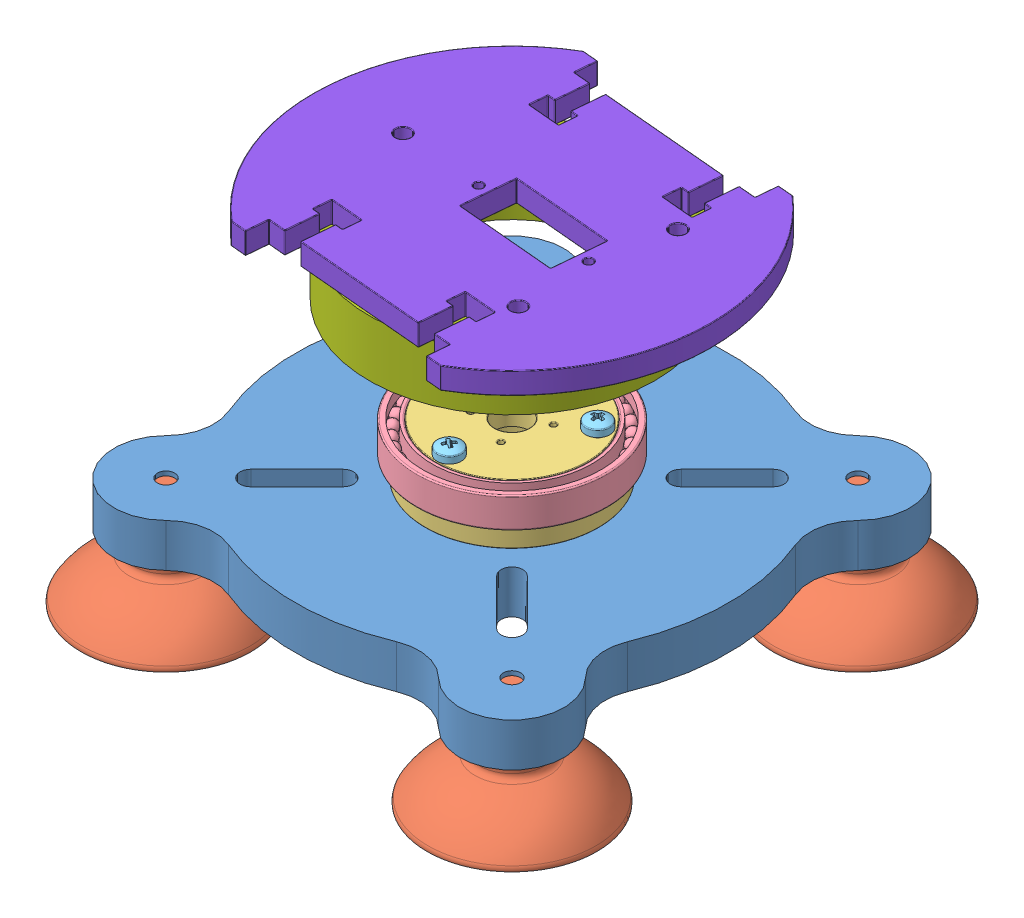
SolidWorks assembly Assem1, configuration Default. Lengths in mm.
Overall size (119.13 78.96 119.13).
15 component instances, 8 part files, 22 mates.
Components (placement in the parent):
- part_12 t310-1: part_12 t310 [Default] at origin size (103.9 10 103.9)
- part_13 t310-1: part_13 t310 [Default] at (-39.9515 -5 -39.9515) x (0 1 0) z (0 0 1) size (24.01 39.22 39.22)
- part_13 t310-5: part_13 t310 [Default] at (39.9515 -5 -39.9515) x (0 1 0) z (-1 0 0) size (24.01 39.22 39.22)
- part_13 t310-6: part_13 t310 [Default] at (39.9515 -5 39.9515) x (0 1 0) z (0 0 -1) size (24.01 39.22 39.22)
- part_13 t310-7: part_13 t310 [Default] at (-39.9515 -5 39.9515) x (0 1 0) z (1 0 0) size (24.01 39.22 39.22)
- part_11 t310-4: part_11 t310 [Default] at (0 10 0) x (0.866025 0 -0.5) z (0.5 0 0.866025) size (40 12 40)
- angular contact ball bearing_68_iso-4: angular contact ball bearing_68_iso [ISO 15 ABB - 3735 - 38,DE,NC,38_68] at (0 18.5 0) x (0 1 0) z (0.746032 0 -0.66591) size (7 44 44)
- pan head cross recess screw_iso-5: pan head cross recess screw_iso [ISO 7045 - M3 x 25 - Z - 25S] at (12.5574 25.1 -7.25) x (0 -1 0) z (0 0 1) size (27.35 5.6 5.6)
- pan head cross recess screw_iso-10: pan head cross recess screw_iso [ISO 7045 - M3 x 25 - Z - 25S] at (-12.5574 24.4 -7.25) x (0 -1 0) z (0.546944 0 -0.837169) size (27.35 5.6 5.6)
- pan head cross recess screw_iso-11: pan head cross recess screw_iso [ISO 7045 - M3 x 25 - Z - 25S] at (0 24.4 14.5) x (0 -1 0) z (0.546944 0 -0.837169) size (27.35 5.6 5.6)
- hex nut style 1 gradeab_iso-1: hex nut style 1 gradeab_iso [ISO - 4032 - M3 - D - S] at (-12.5574 2.6 -7.25) x (1 0 0) z (0 -1 0) size (5.5 6.35 2.4)
- hex nut style 1 gradeab_iso-2: hex nut style 1 gradeab_iso [ISO - 4032 - M3 - D - S] at (0 2.6 14.5) x (1 0 0) z (0 -1 0) size (5.5 6.35 2.4)
- hex nut style 1 gradeab_iso-3: hex nut style 1 gradeab_iso [ISO - 4032 - M3 - D - S] at (12.5574 2.6 -7.25) x (1 0 0) z (0 -1 0) size (5.5 6.35 2.4)
- part_10 t310-1: part_10 t310 [Default] at (0 45.9574 0) x (-0.996058 0 -0.088703) z (0.088703 0 -0.996058) size (66 13 66)
- part_9 t310-1: part_9 t310 [Default] at (0 58.9574 0) x (-0.996058 0 -0.088703) z (0.088703 0 -0.996058) size (92 5 75)
Mates (geometry in assembly coordinates):
- Concentric1: concentric anti-aligned: cylinder of part_12 t310-1 through (-39.9515 10 -39.9515) axis (0 -1 0) radius 2; cylinder of part_13 t310-1 through (-39.9515 9.0072 -39.9515) axis (0 1 0) radius 2.4
- Coincident1: coincident anti-aligned: plane of part_12 t310-1 through (0 0 0) normal (0 -1 0); plane of part_13 t310-1 through (-39.9515 0 -39.9515) normal (0 1 0)
- Concentric2: concentric aligned: cylinder of part_12 t310-1 through (12.5574 10 -7.25) axis (0 -1 0) radius 1.75; cylinder of part_11 t310-4 through (12.5574 22 -7.25) axis (0 -1 0) radius 1.75
- Concentric3: concentric aligned: cylinder of part_12 t310-1 through (12.5574 10 -7.25) axis (0 -1 0) radius 1.75; cylinder of part_11 t310-4 through (12.5574 22 -7.25) axis (0 -1 0) radius 1.75
- Concentric4: concentric anti-aligned: cylinder of part_12 t310-1 through (0 5 0) axis (0 -1 0) radius 21; cylinder of part_11 t310-4 through (0 22 0) axis (0 1 0) radius 20
- Coincident5: coincident anti-aligned: plane of part_12 t310-1 through (0 10 0) normal (0 1 0); circle of part_11 t310-4
- Concentric6: concentric aligned: cylinder of part_11 t310-4 through (0 22 0) axis (0 1 0) radius 17.5; cylinder of angular contact ball bearing_68_iso-4 through (0 -2.1375 0) axis (0 1 0) radius 17.5
- Coincident6: coincident anti-aligned: plane of part_11 t310-4 through (-17.3205 15 10) normal (0 1 0); plane of angular contact ball bearing_68_iso-4 through (12.5524 15 14.0627) normal (0 -1 0)
- Concentric12: concentric anti-aligned: cylinder of part_11 t310-4 through (-12.5574 22 -7.25) axis (0 -1 0) radius 1.75; cylinder of pan head cross recess screw_iso-10 through (-12.5574 49.8 -7.25) axis (0 1 0) radius 2.8
- Concentric131: concentric anti-aligned: cylinder of part_11 t310-4 through (0 22 14.5) axis (0 -1 0) radius 1.75; cylinder of pan head cross recess screw_iso-11 through (0 49.8 14.5) axis (0 1 0) radius 2.8
- Coincident10: coincident anti-aligned: plane of part_11 t310-4 through (-15.1554 22 8.75) normal (0 1 0); plane of pan head cross recess screw_iso-11 through (-1.2558 22 13.6796) normal (0 -1 0)
- Coincident11: coincident anti-aligned: plane of part_11 t310-4 through (-15.1554 22 8.75) normal (0 1 0); plane of pan head cross recess screw_iso-10 through (-13.8131 22 -8.0704) normal (0 -1 0)
- Concentric14: concentric aligned: cylinder of part_12 t310-1 through (-12.5574 10 -7.25) axis (0 -1 0) radius 1.75; cylinder of hex nut style 1 gradeab_iso-1 through (-12.5574 27.6375 -7.25) axis (0 -1 0) radius 1.5
- Coincident12: coincident anti-aligned: plane of part_12 t310-1 through (0 5 0) normal (0 -1 0); plane of hex nut style 1 gradeab_iso-1 through (-12.5574 5 -4.0746) normal (0 1 0)
- Concentric15: concentric aligned: cylinder of part_12 t310-1 through (0 10 14.5) axis (0 -1 0) radius 1.75; cylinder of hex nut style 1 gradeab_iso-2 through (0 27.6375 14.5) axis (0 -1 0) radius 1.5
- Coincident13: coincident anti-aligned: plane of part_12 t310-1 through (0 5 0) normal (0 -1 0); plane of hex nut style 1 gradeab_iso-2 through (0 5 17.6754) normal (0 1 0)
- Concentric16: concentric aligned: cylinder of part_12 t310-1 through (12.5574 10 -7.25) axis (0 -1 0) radius 1.75; cylinder of hex nut style 1 gradeab_iso-3 through (12.5574 27.6375 -7.25) axis (0 -1 0) radius 1.5
- Coincident14: coincident anti-aligned: plane of part_12 t310-1 through (0 5 0) normal (0 -1 0); plane of hex nut style 1 gradeab_iso-3 through (12.5574 5 -4.0746) normal (0 1 0)
- Concentric17: concentric anti-aligned: cylinder of angular contact ball bearing_68_iso-4 through (0 -2.1375 0) axis (0 1 0) radius 22; cylinder of part_10 t310-1 through (0 58.9574 0) axis (0 -1 0) radius 22.25
- Concentric18: concentric aligned: cylinder of part_10 t310-1 through (0 58.9574 0) axis (0 -1 0) radius 33; cylinder of part_9 t310-1 through (0 63.9574 0) axis (0 -1 0) radius 46
- Coincident16: coincident anti-aligned: plane of part_10 t310-1 through (0 58.9574 0) normal (0 1 0); plane of part_9 t310-1 through (0 58.9574 0) normal (0 -1 0)
- Concentric22: concentric aligned: cylinder of part_10 t310-1 through (-27.6406 58.9574 -2.4615) axis (0 -1 0) radius 1.75; cylinder of part_9 t310-1 through (-27.6406 63.9574 -2.4615) axis (0 -1 0) radius 1.75
